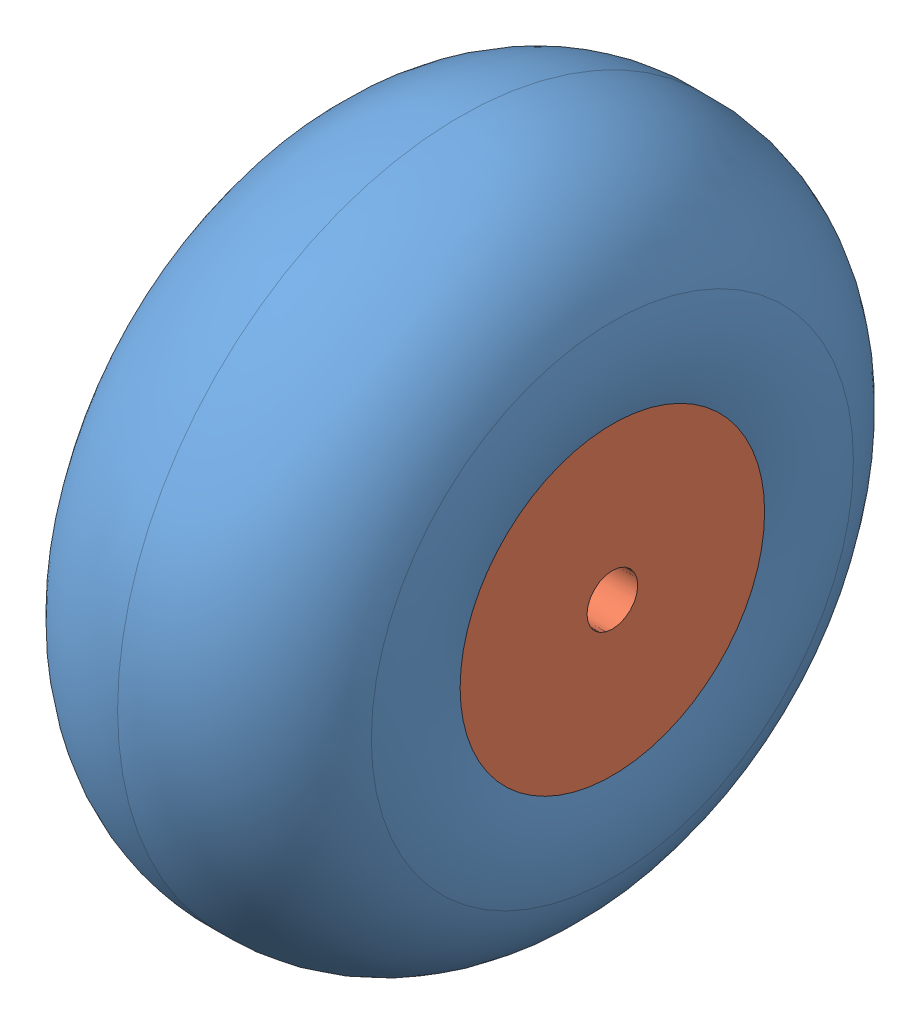
SolidWorks assembly 6.00-6 wheel and tire assembly, configuration Default. Lengths in mm.
Overall size (159.37 343.14 343.14).
2 component instances, 2 part files, 0 mates.
Components (placement in the parent):
- tire 6.00-6-1: tire 6.00-6 [Default] at (-445.3299 120.4843 141.4975) size (159.37 343.14 343.14)
- Wheel 6.00-6-1: Wheel 6.00-6 [Default] at (-470.7299 120.4843 141.4975) size (152.4 165.1 165.1)
